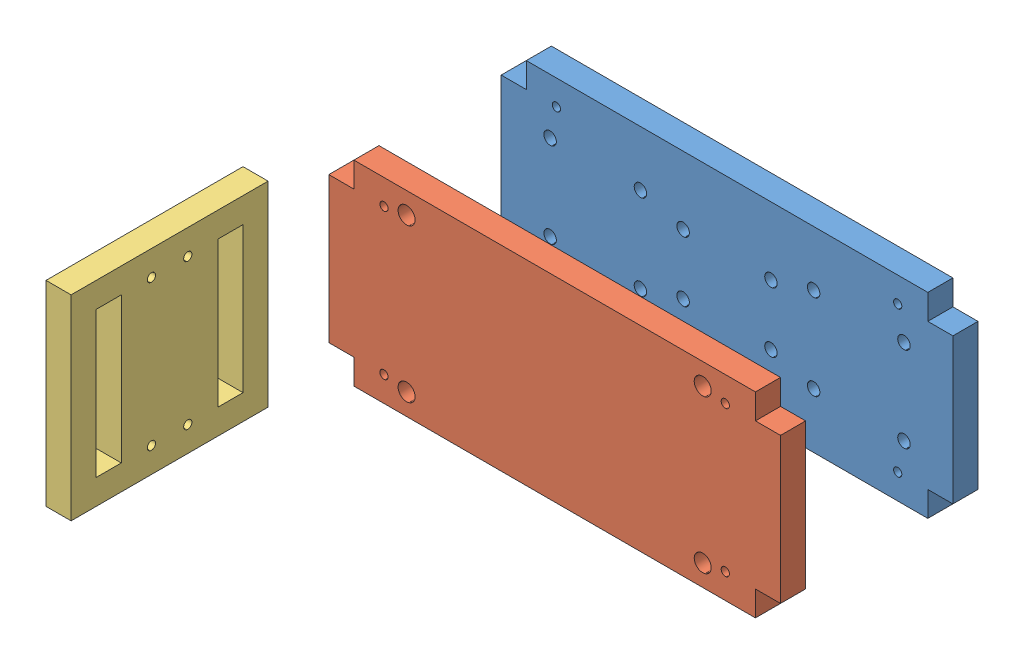
SolidWorks assembly Assem1, configuration Default. Lengths in mm.
Overall size (241.65 129.82 129.72).
3 component instances, 3 part files, 4 mates.
Components (placement in the parent):
- Z back apnel-1: Z back apnel [Default] at (46.7093 111.5301 137.0177) size (180 78 10)
- Z front panel-1: Z front panel [Default] at (46.7093 111.5301 205.7088) size (180 78 10)
- Z side panel-1: Z side panel [Default] at (-104.9384 59.7119 227.4904) size (10 78 78.5)
Mates (geometry in assembly coordinates):
- Concentric1: concentric aligned: cylinder of Z back apnel-1 through (114.7093 140.5301 147.0177) axis (0 0 1) radius 1.65; cylinder of Z front panel-1 through (114.7093 140.5301 215.7088) axis (0 0 1) radius 1.65
- Concentric2: concentric aligned: cylinder of Z back apnel-1 through (114.7093 82.5301 147.0177) axis (0 0 1) radius 1.65; cylinder of Z front panel-1 through (114.7093 82.5301 215.7088) axis (0 0 1) radius 1.65
- Concentric3: concentric aligned: cylinder of Z back apnel-1 through (-21.2907 140.5301 147.0177) axis (0 0 1) radius 1.65; cylinder of Z front panel-1 through (-21.2907 140.5301 215.7088) axis (0 0 1) radius 1.65
- Concentric4: concentric aligned: cylinder of Z back apnel-1 through (-21.2907 82.5301 147.0177) axis (0 0 1) radius 1.65; cylinder of Z front panel-1 through (-21.2907 82.5301 215.7088) axis (0 0 1) radius 1.65
